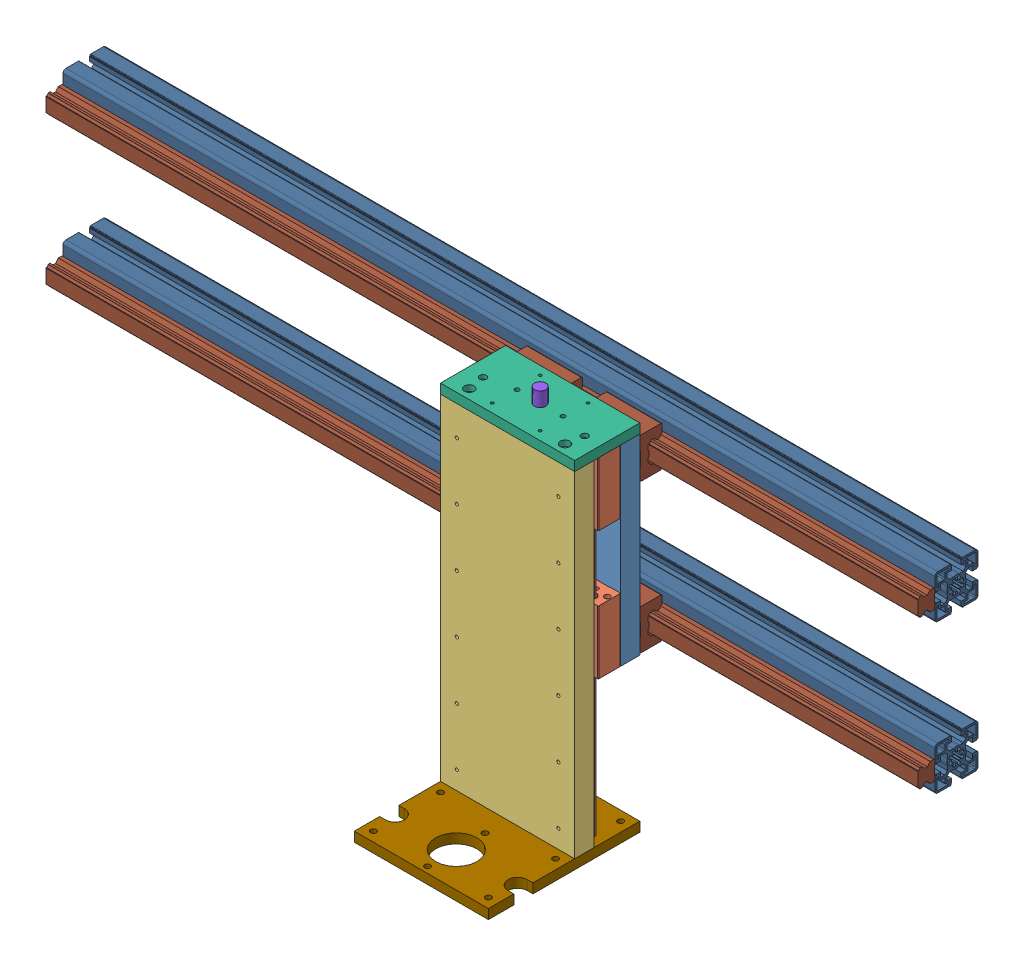
SolidWorks assembly ZY, configuration Default. Lengths in mm.
Overall size (910 385 231).
15 component instances, 11 part files, 19 mates.
Components (placement in the parent):
- Zkızakarabatut-1: Zkızakarabatut [Default] at (-56.5943 -53.5516 66.2462) size (140 200 20)
- Zkızak15-1: Zkızak15 [Default] at (-205.7091 -28.5516 233.6721) x (1 0 0) z (0 1 0) size (34 28 350)
- Zkızak15-2: Zkızak15 [Default] at (-99.7091 -28.5516 233.6721) x (1 0 0) z (0 1 0) size (34 28 350)
- Zkızaktut-1: Zkızaktut [Default] at (83.4057 146.4484 114.2462) x (-1 0 0) z (0 0 1) size (140 350 20)
- 16mmnut-1: 16mmnut [Default] at (13.4057 61.4484 100.2462) x (0 0 -1) z (0 -1 0) size (40 48 50)
- Zsomuntut-1: Zsomuntut [Default] at (13.4057 11.4484 100.2462) x (0 0 -1) z (0 1 0) size (40 72 30)
- Zaltmptprtut-1: Zaltmptprtut [Default] at (-56.5943 156.4484 66.2462) x (1 0 0) z (0 -1 0) size (140 68 10)
- 12mm-1: 12mm [Default] at (13.4057 146.4484 100.2462) x (0 0 -1) z (0 -1 0) size (38 63 16)
- Z16mm-1: Z16mm [Default] at (13.4057 -204.5516 100.2462) x (1 0 0) z (0 1 0) size (16 16 376)
- Zmptprtut-3: Zmptprtut [Default] at (83.4057 -213.5516 66.2462) x (-1 0 0) z (0 1 0) size (140 158 10)
- 12mm-2: 12mm [Default] at (13.4057 -203.5516 100.2462) x (0 0 -1) z (0 1 0) size (38 63 16)
- 45x45-1: 45x45 [Default] at (-546.5943 123.9485 15.7462) x (0 0 -1) z (1 0 0) size (45 45 910)
- 45x45-2: 45x45 [Default] at (-546.5943 -31.0516 15.7462) x (0 0 -1) z (1 0 0) size (45 45 910)
- Ykızak2-1: Ykızak2 [Default] at (-91.5943 326.6381 -159.0432) x (0 -1 0) z (-1 0 0) size (42 28 910)
- Ykızak2-2: Ykızak2 [Default] at (-91.5943 171.638 -159.0432) x (0 -1 0) z (-1 0 0) size (42 28 910)
Mates (geometry in assembly coordinates):
- Coincident1: coincident anti-aligned: plane of Zkızakarabatut-1 through (-56.5943 146.4484 86.2462) normal (0 0 1); plane of Zkızak15-1 through (92.8004 146.4484 86.2462) normal (0 0 -1)
- Coincident2: coincident aligned: plane of Zkızakarabatut-1 through (-56.5943 146.4484 86.2462) normal (0 1 0); plane of Zkızak15-1 through (92.8004 146.4484 327.7718) normal (0 1 0)
- Coincident4: coincident aligned: plane of Zkızakarabatut-1 through (-56.5943 -53.5516 86.2462) normal (-1 0 0); plane of Zkızak15-1 through (-56.5943 146.4484 327.7718) normal (-1 0 0)
- Coincident5: coincident anti-aligned: plane of Zkızakarabatut-1 through (-56.5943 146.4484 86.2462) normal (0 0 1); plane of Zkızak15-2 through (198.8004 12.4484 86.2462) normal (0 0 -1)
- Coincident6: coincident aligned: plane of Zkızakarabatut-1 through (-56.5943 146.4484 86.2462) normal (0 1 0); plane of Zkızak15-2 through (198.8004 146.4484 327.7718) normal (0 1 0)
- Coincident7: coincident aligned: plane of Zkızakarabatut-1 through (83.4057 -53.5516 86.2462) normal (1 0 0); plane of Zkızak15-2 through (83.4057 146.4484 327.7718) normal (1 0 0)
- Concentric2: concentric anti-aligned: cylinder of 16mmnut-1; cylinder of Zsomuntut-1
- Coincident18: coincident: line of 16mmnut-1; plane of Zsomuntut-1 through (49.4057 51.4484 80.2462) normal (0 1 0)
- Coincident59: coincident anti-aligned: plane of Zaltmptprtut-1 through (-56.5943 146.4484 134.2462) normal (0 -1 0); plane of 12mm-1 through (-43.9622 146.4484 100.2462) normal (0 1 0)
- Coincident66: coincident aligned: plane of 45x45-1 through (-546.5943 101.9485 22.0462) normal (-1 0 0); plane of 45x45-2 through (-546.5943 -53.0516 22.0462) normal (-1 0 0)
- Coincident85: coincident aligned: plane of 45x45-1 through (363.4057 117.6486 -6.7539) normal (0 0 -1); plane of 45x45-2 through (363.4057 -24.7517 -6.7539) normal (0 0 -1)
- Coincident86: coincident aligned: plane of Zkızakarabatut-1 through (-56.5943 146.4484 86.2462) normal (0 1 0); plane of 45x45-1 through (363.4057 146.4484 35.2462) normal (0 1 0)
- Coincident87: coincident aligned: plane of Zkızakarabatut-1 through (-56.5943 -53.5516 86.2462) normal (0 -1 0); plane of 45x45-2 through (363.4057 -53.5516 22.0462) normal (0 -1 0)
- Coincident93: coincident: plane of 45x45-1 through (363.4057 130.2484 38.2462) normal (0 0 1); line of Ykızak2-1
- Coincident98: coincident: plane of 45x45-2 through (363.4057 -24.7517 38.2462) normal (0 0 1); line of Ykızak2-2
- Coincident99: coincident anti-aligned: plane of Zkızakarabatut-1 through (-22.5943 58.3484 80.2462) normal (1 0 0); plane of Zsomuntut-1 through (-22.5943 51.4484 120.2462) normal (-1 0 0)
- Coincident100: coincident: point of Zkızaktut-1; point of Zaltmptprtut-1
- Coincident101: coincident aligned: plane of Zkızaktut-1; plane of Zaltmptprtut-1
- Coincident102: coincident aligned: plane of Zkızaktut-1; plane of Zaltmptprtut-1
